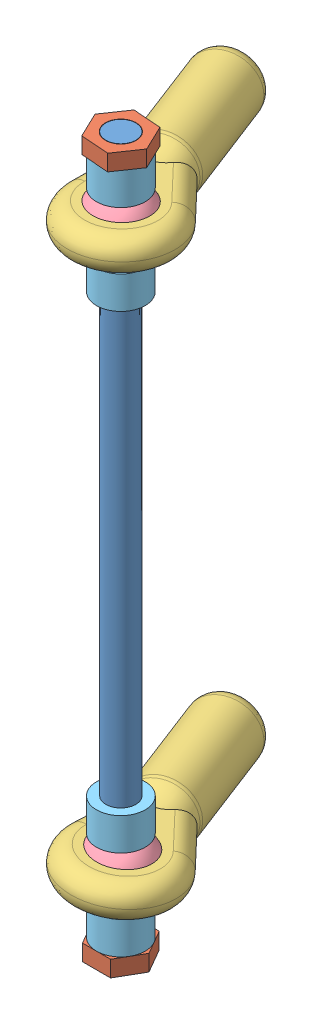
SolidWorks assembly wrist, configuration Default. Lengths in mm.
Overall size (19.42 69.85 27.59).
13 component instances, 5 part files, 17 mates.
Components (placement in the parent):
- elbow_rod-1: elbow_rod [Default] at (-9.1612 -25.5522 3.8591) size (2.95 69.85 2.95)
- 4-40_nut-2: 4-40_nut [Default] at (-9.1612 42.7103 3.8591) x (0.997098 0 0.07613) z (-0.07613 0 0.997098) size (5.5 1.59 4.76)
- balljoint-1: balljoint [Default] at (-16.2865 36.1095 -7.742) x (-0.378139 -0.034292 -0.925113) z (0.925634 0.001735 -0.378416) size (25.24 5.95 10.32) (flexible)
  - balljoint_joint-1: balljoint_joint [Default] at (-6.0674 0.1484 2.2064) size (25.24 5.95 10.32)
  - balljoint_ball-2: balljoint_ball [Default] at (-13.4478 0.1484 2.2064) x (-0.784932 -0.028008 0.618948) z (-0.618632 -0.019863 -0.78543) size (6.35 5.63 6.35)
- 4-40_spacer-1: 4-40_spacer [Default] at (-9.1612 39.5353 3.8591) x (-0.821485 0 -0.57023) z (0.57023 0 -0.821485) size (4.76 3.17 4.76)
- 4-40_spacer-2: 4-40_spacer [Default] at (-9.1612 30.7353 3.8591) x (0.999786 0 -0.020674) z (0.020674 0 0.999786) size (4.76 3.17 4.76)
- 4-40_spacer-4: 4-40_spacer [Default] at (-9.1612 -23.9647 3.8591) size (4.76 3.17 4.76)
- 4-40_spacer-5: 4-40_spacer [Default] at (-9.1612 -15.1646 3.8591) x (0.985018 0 0.172451) z (-0.172451 0 0.985018) size (4.76 3.17 4.76)
- 4-40_nut-4: 4-40_nut [Default] at (-9.1612 -25.5522 3.8591) size (5.5 1.59 4.76)
- balljoint-2: balljoint [Default] at (-16.2934 -18.4271 -7.7453) x (-0.378139 -0.034292 -0.925113) z (0.92418 -0.072137 -0.375084) size (25.24 6.24 10.32) (flexible)
  - balljoint_joint-1: balljoint_joint [Default] at (-6.0674 0.1484 2.2064) size (25.24 5.95 10.32)
  - balljoint_ball-2: balljoint_ball [Default] at (-13.4478 0.1484 2.2064) x (0.135407 0.076148 0.98786) z (-0.990196 -0.024108 0.137585) size (6.35 5.63 6.35)
Mates (geometry in assembly coordinates):
- Concentric1: concentric aligned: circle of elbow_rod-1; circle of 4-40_nut-2
- Coincident1: coincident aligned: plane of elbow_rod-1 through (-9.1612 44.2978 3.8591) normal (0 1 0); plane of 4-40_nut-2 through (-7.6091 44.2978 1.5894) normal (0 1 0)
- Concentric6: concentric aligned: cylinder of elbow_rod-1 through (-9.1612 44.2978 3.8591) axis (0 -1 0) radius 1.4732; cylinder of 4-40_spacer-1 through (-9.1612 42.7103 3.8591) axis (0 -1 0) radius 1.4605
- Coincident4: coincident anti-aligned: plane of 4-40_nut-2 through (-7.6091 42.7103 1.5894) normal (0 -1 0); plane of 4-40_spacer-1 through (-9.1612 42.7103 3.8591) normal (0 1 0)
- Concentric7: concentric aligned: cylinder of elbow_rod-1 through (-9.1612 44.2978 3.8591) axis (0 -1 0) radius 1.4732; cylinder of 4-40_spacer-2 through (-9.1612 33.9103 3.8591) axis (0 -1 0) radius 1.4605
- Concentric8: concentric aligned: cylinder of elbow_rod-1 through (-9.1612 44.2978 3.8591) axis (0 -1 0) radius 1.4732; cylinder of 4-40_nut-4 through (-9.1612 -23.9647 3.8591) axis (0 -1 0) radius 1.4986
- Coincident8: coincident aligned: plane of elbow_rod-1 through (-9.1612 -25.5522 3.8591) normal (0 -1 0); plane of 4-40_nut-4 through (-7.7864 -25.5522 1.4779) normal (0 -1 0)
- Coincident9: coincident anti-aligned: plane of 4-40_spacer-4 through (-9.1612 -23.9647 3.8591) normal (0 -1 0); plane of 4-40_nut-4 through (-7.7864 -23.9647 1.4779) normal (0 1 0)
- Concentric9: concentric aligned: cylinder of elbow_rod-1 through (-9.1612 44.2978 3.8591) axis (0 -1 0) radius 1.4732; cylinder of 4-40_spacer-4 through (-9.1612 -20.7897 3.8591) axis (0 -1 0) radius 1.4605
- Concentric11: concentric aligned: cylinder of elbow_rod-1 through (-9.1612 44.2978 3.8591) axis (0 -1 0) radius 1.4732; cylinder of 4-40_spacer-5 through (-9.1612 -11.9896 3.8591) axis (0 -1 0) radius 1.4605
- Parallel1: parallel aligned: cylinder of balljoint-1/balljoint_joint-1 through (363.9449 70.5584 916.6591) axis (0.378139 0.034292 0.925113) radius 2.9766; cylinder of balljoint-2/balljoint_joint-1 through (363.9449 15.8585 916.6591) axis (0.378139 0.034292 0.925113) radius 2.9766
- Concentric13: concentric aligned: cylinder of elbow_rod-1 through (-9.1612 44.2978 3.8591) axis (0 -1 0) radius 1.4732; cylinder of balljoint-1/balljoint_ball-2 through (-9.1612 -963.2772 3.8591) axis (0 -1 0) radius 1.4732
- Concentric14: concentric aligned: cylinder of elbow_rod-1 through (-9.1612 44.2978 3.8591) axis (0 -1 0) radius 1.4732; cylinder of balljoint-2/balljoint_ball-2 through (-9.1612 -1017.9772 3.8591) axis (0 -1 0) radius 1.4732
- Coincident17: coincident aligned: circle of balljoint-1/balljoint_ball-2; plane of 4-40_spacer-1 through (-9.1612 39.5353 3.8591) normal (0 -1 0)
- Coincident18: coincident anti-aligned: circle of balljoint-1/balljoint_ball-2; plane of 4-40_spacer-2 through (-9.1612 33.9103 3.8591) normal (0 1 0)
- Coincident19: coincident anti-aligned: plane of 4-40_spacer-4 through (-9.1612 -20.7897 3.8591) normal (0 1 0); circle of balljoint-2/balljoint_ball-2
- Coincident20: coincident aligned: plane of 4-40_spacer-5 through (-9.1612 -15.1646 3.8591) normal (0 -1 0); circle of balljoint-2/balljoint_ball-2
